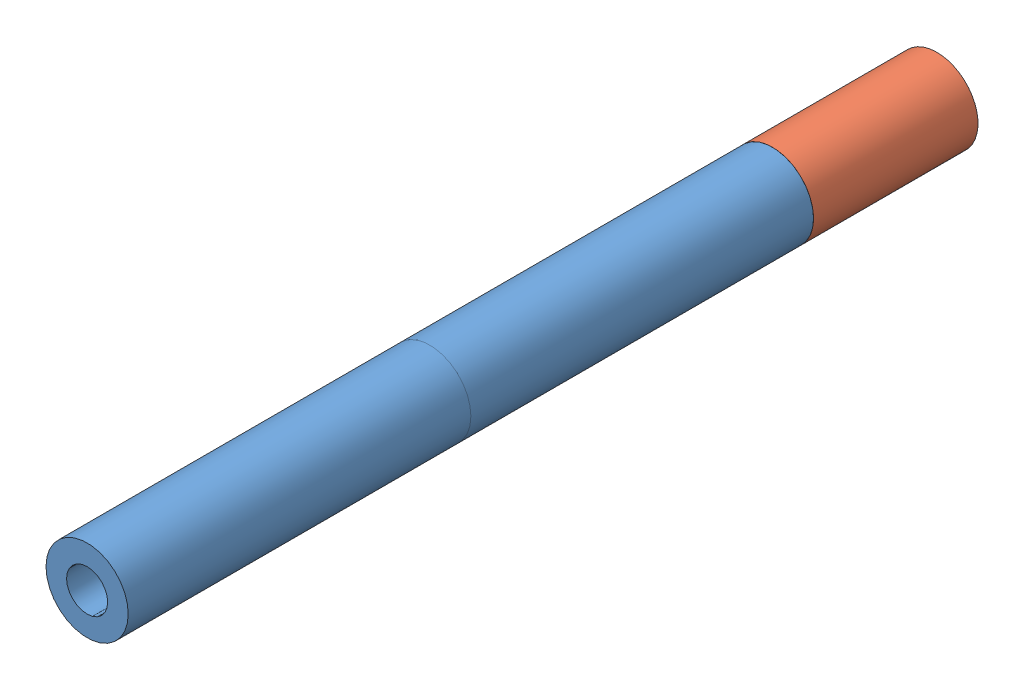
SolidWorks assembly Assem45, configuration Default. Lengths in mm.
Overall size (6 6 62).
3 component instances, 2 part files, 4 mates.
Components (placement in the parent):
- Board_Spacer_large-1: Board_Spacer_large [Default] at (9.0041 14.1355 7.6616) size (6 6 25)
- Board_Spacer_small-1: Board_Spacer_small [Default] at (9.0041 14.1355 -4.3384) size (6 6 12)
- Board_Spacer_large-2: Board_Spacer_large [Default] at (9.0041 14.1355 32.6616) size (6 6 25)
Mates (geometry in assembly coordinates):
- Coincident1: coincident: plane of Board_Spacer_large-1 through (9.0041 14.1355 7.6616) normal (0 0 -1); plane of Board_Spacer_small-1 through (9.0041 14.1355 7.6616) normal (0 0 1)
- Coincident2: coincident: circle of Board_Spacer_large-1; circle of Board_Spacer_small-1
- Coincident3: coincident: plane of Board_Spacer_large-1 through (9.0041 14.1355 32.6616) normal (0 0 1); plane of Board_Spacer_large-2 through (9.0041 14.1355 32.6616) normal (0 0 -1)
- Coincident5: coincident: circle of Board_Spacer_large-1; circle of Board_Spacer_large-2
